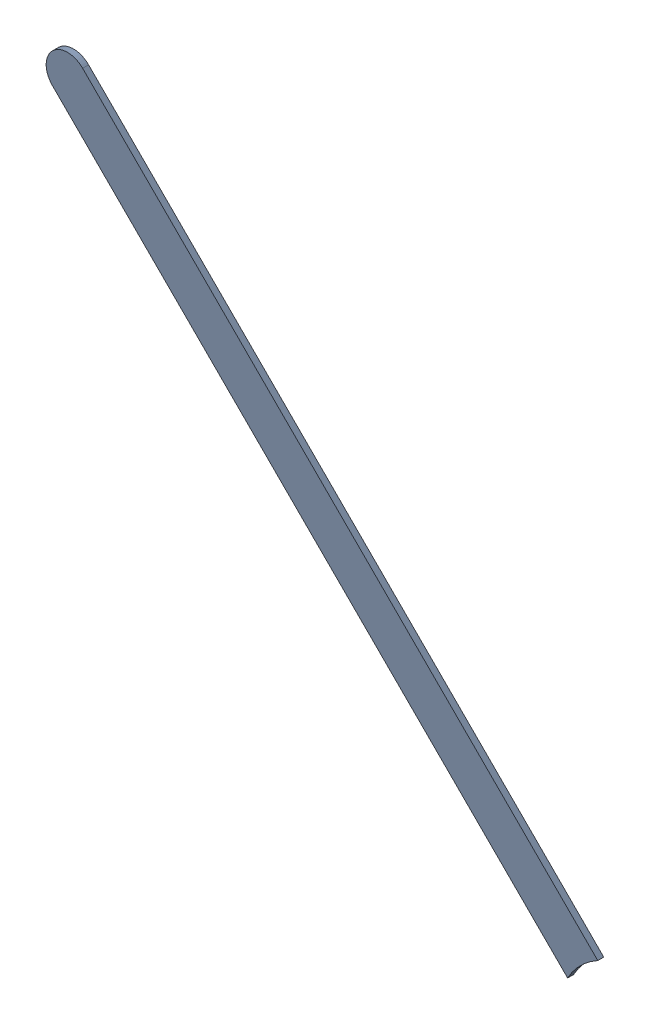
SolidWorks assembly Track (17.2mm,51.761mm)(20.574mm,48.387mm) on Bottom Layer, configuration Predeterminado. Lengths in mm.
Overall size (3.29 3.29 0.04).
2 component instances, 1 part files, 0 mates.
Components (placement in the parent):
- Track (17.2mm,51.761mm)(20.574mm,48.387mm) on Bottom Layer-1-1: Track (17.2mm,51.761mm)(20.574mm,48.387mm) on Bottom Layer-1 [Predeterminado] at (-68.317 -44.187 -0.4013) size (3.29 3.29 0.04)
  - Track (17.2mm,51.761mm)(20.574mm,48.387mm) on Bottom Layer-Part-1-1: Track (17.2mm,51.761mm)(20.574mm,48.387mm) on Bottom Layer-Part-1 [Predeterminado] at origin size (3.29 3.29 0.04)
